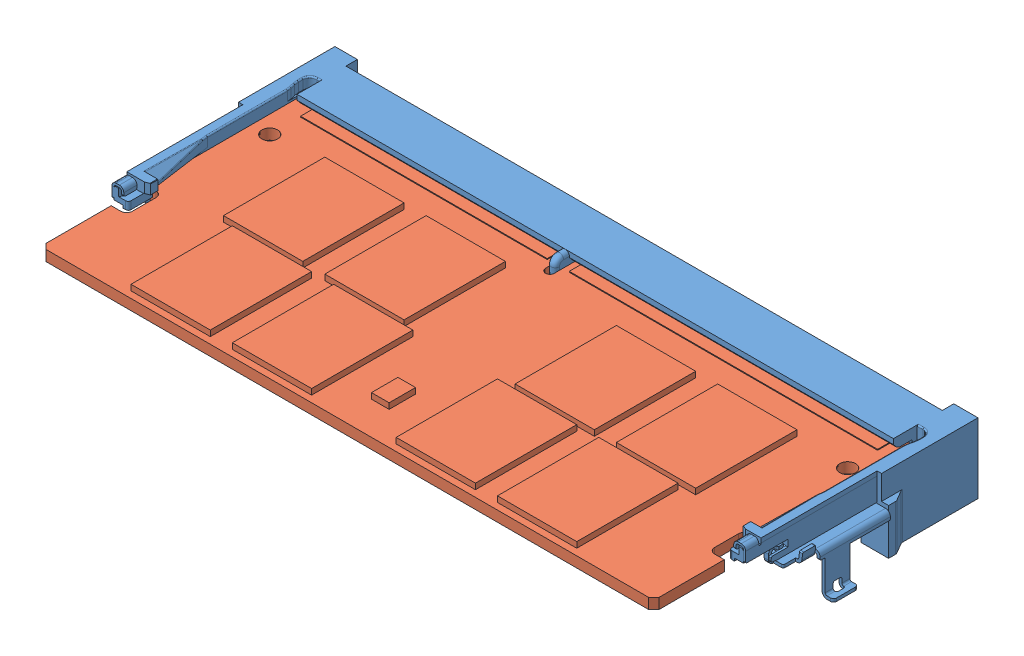
SolidWorks assembly DDR4, configuration Default. Lengths in mm.
Overall size (77.02 8.49 35.1).
2 component instances, 2 part files, 6 mates.
Components (placement in the parent):
- c-2309411-1-1-3d-1: c-2309411-1-1-3d [Default] at (0 4.0804 20.845) size (77.02 8.49 25.85)
- DDR4-Board-1: DDR4-Board [Default] at (0 5.6054 15.094) x (-1 0 0) z (0 1 0) size (69.6 30 2.5)
Mates (geometry in assembly coordinates):
- Coincident1: coincident aligned: plane of c-2309411-1-1-3d-1 through (0 4.0804 0) normal (0 0 1)
- Coincident2: coincident anti-aligned: plane of c-2309411-1-1-3d-1 through (-37.5702 0 6.595) normal (0 -1 0)
- Coincident3: coincident aligned: plane of c-2309411-1-1-3d-1 through (0 4.0804 20.845) normal (1 0 0)
- Width1: width: plane of DDR4-Board-1 through (0 6.9054 13.1714) normal (0 1 0); plane of c-2309411-1-1-3d-1 through (0 5.5054 13.1714) normal (0 -1 0); plane of DDR4-Board-1 through (-34.95 6.8853 -0.255) normal (0 -1 0); plane of c-2309411-1-1-3d-1 through (0 5.5254 20.845) normal (0 1 0)
- Width2: width: plane of DDR4-Board-1 through (-4 5.6054 -1.8286) normal (1 0 0); plane of c-2309411-1-1-3d-1 through (-3 5.6054 -1.8286) normal (-1 0 0); plane of DDR4-Board-1 through (-3.97 4.0804 20.845) normal (-1 0 0); plane of c-2309411-1-1-3d-1 through (-3.03 4.0804 20.845) normal (1 0 0)
- Coincident4: coincident anti-aligned: plane of c-2309411-1-1-3d-1 through (-33.95 8.0554 18.094) normal (0 0 -1); plane of DDR4-Board-1 through (-36.55 5.6054 18.094) normal (0 0 1)
